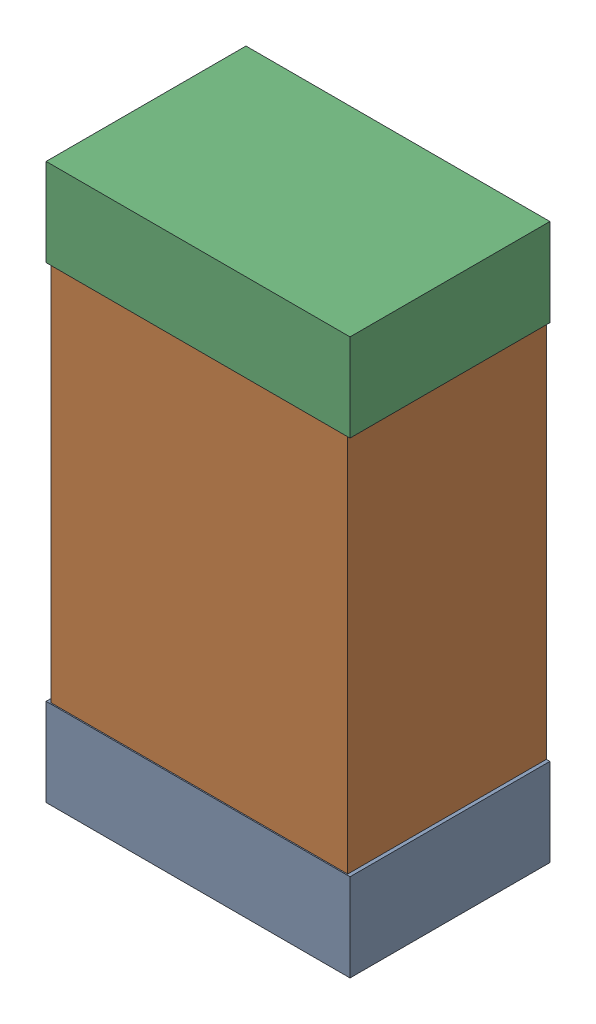
SolidWorks assembly C6Kanaloa_v2.0.0_Power, configuration Default. Lengths in mm.
Overall size (1.3 2.38 0.85).
6 component instances, 2 part files, 0 mates.
Components (placement in the parent):
- 330415056-1: 330415056 [Default] at (98.1322 79.7992 0) size (1.3 0.38 0.85)
  - Extruded_2-1: Extruded_2 [Default] at origin size (1.3 0.38 0.85)
- 352877008-1: 352877008 [Default] at (98.1322 80.7992 0) size (1.27 2.2 0.85)
  - Extruded_3-1: Extruded_3 [Default] at origin size (1.27 2.2 0.85)
- 330415056-2: 330415056 [Default] at (98.1322 81.7992 0) size (1.3 0.38 0.85)
  - Extruded_2-1: Extruded_2 [Default] at origin size (1.3 0.38 0.85)
